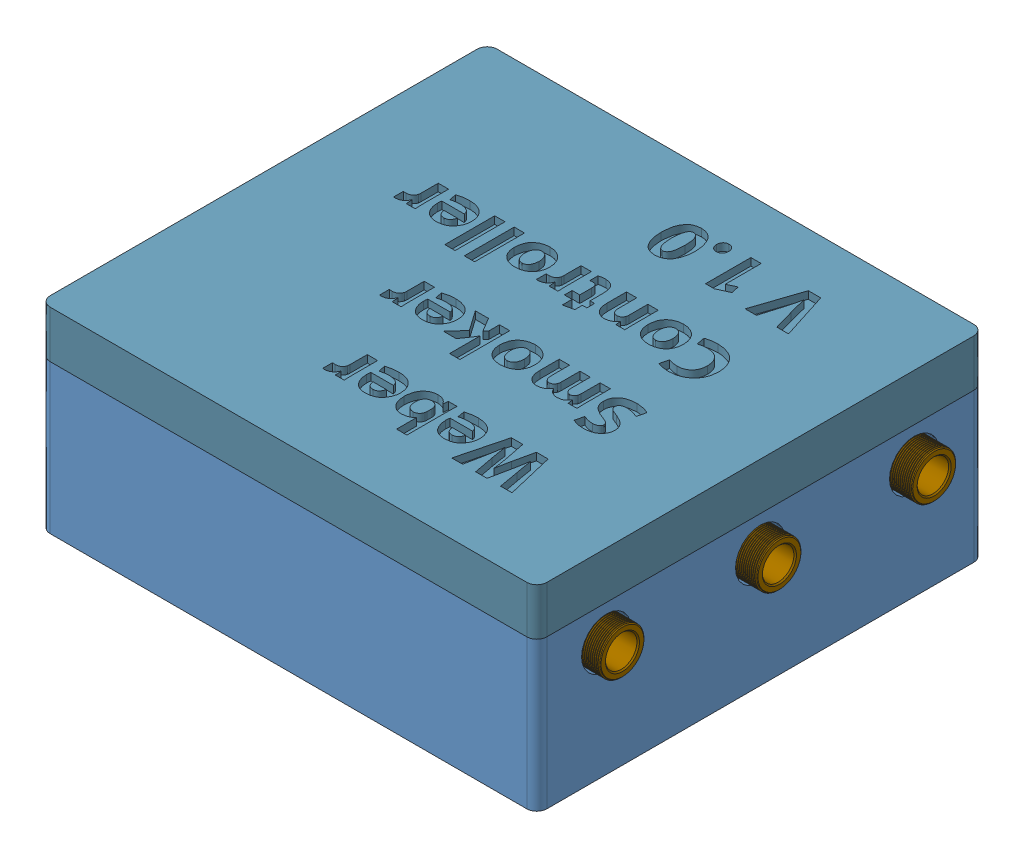
SolidWorks assembly controller, configuration Default. Lengths in mm.
Overall size (108.36 39.5 90).
121 component instances, 50 part files, 20 mates.
Components (placement in the parent):
- box-1: box [Default] at (28.3215 40.8238 49.104) size (100 35 90)
- adafruit esp8266 feather-1: adafruit esp8266 feather [Default] at (-8.3947 55.8238 40.0665) x (0 0 1) z (0 1 0) size (51.25 22.86 3.97)
  - adafruit esp8266 feather-1: adafruit esp8266 feather [Default] at origin size (50.8 22.86 1.6)
  - 0805NO_10UF-1: 0805NO_10UF [Default] at (21.3793 16.0687 1.6213) x (0.148132 -0.963382 0.223501) z (0.165546 0.24696 0.95478) size (2.2 1.45 1)
  - 0805NO_10_F-1: 0805NO_10_F [Default] at (11.049 12.192 1.6) x (-1 0 0) z (0 0 1) size (2.2 1.45 1)
  - 0805NO_10_F-2: 0805NO_10_F [Default] at (8.088 12.959 1.6) x (0 1 0) z (0 0 1) size (2.2 1.45 1)
  - 0805NO_10_F-3: 0805NO_10_F [Default] at (14.366 12.64 1.6) x (0 -1 0) z (0 0 1) size (2.2 1.45 1)
  - 0603NO_1UF-1: 0603NO_1UF [Default] at (12.302 4.775 1.6) x (0 -1 0) z (0 0 1) size (3 1.48 1)
  - CHIPLED_0805_NOOUTLINE_ORANGE-1: CHIPLED_0805_NOOUTLINE_ORANGE [Default] at (2.413 5.588 1.6) x (0 -1 0) z (0 0 1) size (1.25 2 1)
  - CHIPLED_0805_NOOUTLINE_RED-1: CHIPLED_0805_NOOUTLINE_RED [Default] at (2.8575 17.3355 1.6) x (0 -1 0) z (0 0 1) size (1.25 2 1)
  - SOD123_MBR120-1: SOD123_MBR120 [Default] at (17.907 18.796 1.6) x (-1 0 0) z (0 0 1) size (3.45 1.5 1)
  - QFN24_4MM_SMSC_CP2104-1: QFN24_4MM_SMSC_CP2104 [Default] at (16.256 6.477 1.6) size (5.38 4.1 1)
  - 1X16_ROUND_JP1_1X16_ROUND-1: 1X16_ROUND_JP1_1X16_ROUND [Default] at (25.4 1.27 1.6) x (-1 0 0) z (0 0 1) size (39.73 1.47 1)
  - 1X12_ROUND_JP3_1X12_ROUND-1: 1X12_ROUND_JP3_1X12_ROUND [Default] at (30.48 21.59 1.6) size (29.57 1.47 1)
  - SOT233_MMBT2222-1: SOT233_MMBT2222 [Default] at (24.003 8.001 1.6) x (-1 0 0) z (0 0 1) size (2.92 1.47 1)
  - SOT233_MMBT2222-2: SOT233_MMBT2222 [Default] at (24.003 14.986 1.6) size (2.92 1.47 1)
  - 0603NO_10K-1: 0603NO_10K [Default] at (24.257 18.923 1.6) x (-1 0 0) z (0 0 1) size (3 1.48 1)
  - 0603NO_10K-2: 0603NO_10K [Default] at (24.257 17.526 1.6) x (-1 0 0) z (0 0 1) size (3 1.48 1)
  - 0603NO_10K-3: 0603NO_10K [Default] at (24.003 11.938 1.6) x (-1 0 0) z (0 0 1) size (3 1.48 1)
  - 0603NO_10K-4: 0603NO_10K [Default] at (17.78 17.272 1.6) size (3 1.48 1)
  - 0603NO_10K-5: 0603NO_10K [Default] at (24.384 5.334 1.6) x (-1 0 0) z (0 0 1) size (3 1.48 1)
  - 0603NO_1K-1: 0603NO_1K [Default] at (6.223 4.191 1.6) size (3 1.48 1)
  - 0603NO_1K-2: 0603NO_1K [Default] at (5.588 21.082 1.6) x (0 -1 0) z (0 0 1) size (3 1.48 1)
  - _0603MP_10K-1: _0603MP_10K [Default] at (24.003 10.541 1.6) size (1.6 0.8 1)
  - 0603NO_4_7K-1: 0603NO_4_7K [Default] at (24.384 3.937 1.6) size (3 1.48 1)
  - 0603NO_10K_-1: 0603NO_10K_ [Default] at (20.828 12.7 1.6) x (0 -1 0) z (0 0 1) size (3 1.48 1)
  - _0603MP_1K-1: _0603MP_1K [Default] at (19.812 8.382 1.6) x (0 -1 0) z (0 0 1) size (1.6 0.8 1)
  - SOLDERJUMPER_CLOSEDWIRE_SJ1_SOLDERJUMPER_CLOSEDWIRE-1: SOLDERJUMPER_CLOSEDWIRE_SJ1_SOLDERJUMPER_CLOSEDWIRE [Default] at (12.827 9.779 1.6) x (-1 0 0) z (0 0 1) size (3.3 2.13 1)
  - BTN_KMR2_4_6X2_8_KMR2-1: BTN_KMR2_4_6X2_8_KMR2 [Default] at (9.398 6.35 1.6) x (0 -1 0) z (0 0 1) size (4.2 3.05 1)
  - ADAFRUIT_5MM_U_7_ADAFRUIT_5MM-1: ADAFRUIT_5MM_U_7_ADAFRUIT_5MM [Default] at (45.6565 13.9065 0) x (0 1 0) z (0 0 -1) size (4.88 4.87 1)
  - FEATHERLOGO_U_9_FEATHERLOGO-1: FEATHERLOGO_U_9_FEATHERLOGO [Default] at (30.6705 4.8895 0) x (-1 0 0) z (0 0 -1) size (24.3 11.26 1)
  - PCBFEATREV040_U_13_PCBFEATREV040-1: PCBFEATREV040_U_13_PCBFEATREV040 [Default] at (4.6355 11.2395 0) x (-1 0 0) z (0 0 -1) size (2.1 2.1 1)
  - ADAFRUIT_3_5MM_U_15_ADAFRUIT_3_5MM-1: ADAFRUIT_3_5MM_U_15_ADAFRUIT_3_5MM [Default] at (19.05 4.064 1.6) size (3.79 3.79 1)
  - HUZZAHLOGO_U_23_HUZZAHLOGO-1: HUZZAHLOGO_U_23_HUZZAHLOGO [Default] at (49.911 10.287 0) x (-1 0 0) z (0 0 -1) size (17.77 2.78 1)
  - FIDUCIAL_1MM_FIDUCIAL__-1: FIDUCIAL_1MM_FIDUCIAL__ [Default] at (10.795 20.066 1.6) x (0 -1 0) z (0 0 1) size (1.25 1.25 1)
  - FIDUCIAL_1MM_FIDUCIAL__-2: FIDUCIAL_1MM_FIDUCIAL__ [Default] at (41.5762 11.691 1.6) x (0 -1 0) z (0 0 1) size (1.25 1.25 1)
  - SOT235_SPX3819-1: SOT235_SPX3819 [Default] at (17.78 14.986 1.6) x (0 1 0) z (0 0 1) size (3.3 3 1)
  - SOT235_MCP73831T2ACI_OT-1: SOT235_MCP73831T2ACI_OT [Default] at (17.78 11.557 1.6) x (0 -1 0) z (0 0 1) size (3.3 3 1)
  - JSTPH2_JSTPH-1: JSTPH2_JSTPH [Default] at (10.795 19.304 1.6) size (8.2 7.6 1)
  - ESP12E_ESP12-1: ESP12E_ESP12 [Default] at (36.322 11.43 1.6) x (0 -1 0) z (0 0 1) size (16.13 24.06 1)
  - 4UCONN_20329_V2_20329-1: 4UCONN_20329_V2_20329 [Default] at (4.445 11.43 1.6) x (0 -1 0) z (0 0 1) size (10.1 6.4 1)
- adafruit max31850-1: adafruit max31850 [Default] at (16.5415 55.8238 55.4665) x (0 0 1) z (0 1 0) size (20.32 20.32 3.6)
  - adafruit max31850-1: adafruit max31850 [Default] at origin size (20.32 20.32 1.6)
  - 0805NO_10UF-1: 0805NO_10UF [Default] at (2.968 6 1.6) x (-1 0 0) z (0 0 1) size (2.2 1.45 1)
  - 0805NO_10UF-2: 0805NO_10UF [Default] at (2.874 12.638 1.6) size (2.2 1.45 1)
  - 0805NO_0_1UF-1: 0805NO_0_1UF [Default] at (10.46 10.476 1.6) size (2.2 1.45 1)
  - 0805_FERRITE-1: 0805_FERRITE [Default] at (8.4 12.257 1.6) size (3.8 2 1)
  - 0805_FERRITE-2: 0805_FERRITE [Default] at (12.082 12.257 1.6) x (-1 0 0) z (0 0 1) size (3.8 2 1)
  - FIDUCIAL_1MM_FIDUCIAL__-1: FIDUCIAL_1MM_FIDUCIAL__ [Default] at (13.43 9.952 1.6) size (1.25 1.25 1)
  - FIDUCIAL_1MM_FIDUCIAL__-2: FIDUCIAL_1MM_FIDUCIAL__ [Default] at (1.283 14.636 1.6) size (1.25 1.25 1)
  - SOLDERJUMPER_2WAY_OPEN_NOPASTE_SJ1_SOLDERJUMPER_2WAY_OPEN_NOPASTE-1: SOLDERJUMPER_2WAY_OPEN_NOPASTE_SJ1_SOLDERJUMPER_2WAY_OPEN_NOPASTE [Default] at (17.78 12.954 0) x (-1 0 0) z (0 0 -1) size (4.57 2.13 1)
  - SOLDERJUMPER_2WAY_OPEN_NOPASTE_SJ2_SOLDERJUMPER_2WAY_OPEN_NOPASTE-1: SOLDERJUMPER_2WAY_OPEN_NOPASTE_SJ2_SOLDERJUMPER_2WAY_OPEN_NOPASTE [Default] at (17.78 10.414 0) x (-1 0 0) z (0 0 -1) size (4.57 2.13 1)
  - SOLDERJUMPER_2WAY_OPEN_NOPASTE_SJ3_SOLDERJUMPER_2WAY_OPEN_NOPASTE-1: SOLDERJUMPER_2WAY_OPEN_NOPASTE_SJ3_SOLDERJUMPER_2WAY_OPEN_NOPASTE [Default] at (17.78 7.874 0) x (-1 0 0) z (0 0 -1) size (4.57 2.13 1)
  - SOLDERJUMPER_2WAY_OPEN_NOPASTE_SJ4_SOLDERJUMPER_2WAY_OPEN_NOPASTE-1: SOLDERJUMPER_2WAY_OPEN_NOPASTE_SJ4_SOLDERJUMPER_2WAY_OPEN_NOPASTE [Default] at (17.78 5.334 0) x (-1 0 0) z (0 0 -1) size (4.57 2.13 1)
  - ADAFRUIT_3_5MM_U_18_ADAFRUIT_3_5MM-1: ADAFRUIT_3_5MM_U_18_ADAFRUIT_3_5MM [Default] at (8.001 7.493 0) x (-1 0 0) z (0 0 -1) size (3.79 3.79 1)
  - ADAFRUIT_3_5MM_U_19_ADAFRUIT_3_5MM-1: ADAFRUIT_3_5MM_U_19_ADAFRUIT_3_5MM [Default] at (4.064 8.128 1.6) size (3.79 3.79 1)
  - TDFN10_3X4MM_MAX31850-1: TDFN10_3X4MM_MAX31850 [Default] at (10.206 7.73 1.6) x (0 -1 0) z (0 0 1) size (3.45 5.3 1)
  - SOT235_MIC52253_3-1: SOT235_MIC52253_3 [Default] at (2.366 9.034 1.6) size (3.3 3 1)
  - TERMBLOCK_1X23_5MM_3_5MM-1: TERMBLOCK_1X23_5MM_3_5MM [Default] at (10.16 16.637 1.6) x (-1 0 0) z (0 0 1) size (7.1 7.1 1)
- adafruit max31850-3: adafruit max31850 [Default] at (16.5415 56.3415 78.4665) x (0 0 1) z (0 1 0) size (20.32 20.32 3.6)
  - adafruit max31850-1: adafruit max31850 [Default] at origin size (20.32 20.32 1.6)
  - 0805NO_10UF-1: 0805NO_10UF [Default] at (2.968 6 1.6) x (-1 0 0) z (0 0 1) size (2.2 1.45 1)
  - 0805NO_10UF-2: 0805NO_10UF [Default] at (2.874 12.638 1.6) size (2.2 1.45 1)
  - 0805NO_0_1UF-1: 0805NO_0_1UF [Default] at (10.46 10.476 1.6) size (2.2 1.45 1)
  - 0805_FERRITE-1: 0805_FERRITE [Default] at (8.4 12.257 1.6) size (3.8 2 1)
  - 0805_FERRITE-2: 0805_FERRITE [Default] at (12.082 12.257 1.6) x (-1 0 0) z (0 0 1) size (3.8 2 1)
  - FIDUCIAL_1MM_FIDUCIAL__-1: FIDUCIAL_1MM_FIDUCIAL__ [Default] at (13.43 9.952 1.6) size (1.25 1.25 1)
  - FIDUCIAL_1MM_FIDUCIAL__-2: FIDUCIAL_1MM_FIDUCIAL__ [Default] at (1.283 14.636 1.6) size (1.25 1.25 1)
  - SOLDERJUMPER_2WAY_OPEN_NOPASTE_SJ1_SOLDERJUMPER_2WAY_OPEN_NOPASTE-1: SOLDERJUMPER_2WAY_OPEN_NOPASTE_SJ1_SOLDERJUMPER_2WAY_OPEN_NOPASTE [Default] at (17.78 12.954 0) x (-1 0 0) z (0 0 -1) size (4.57 2.13 1)
  - SOLDERJUMPER_2WAY_OPEN_NOPASTE_SJ2_SOLDERJUMPER_2WAY_OPEN_NOPASTE-1: SOLDERJUMPER_2WAY_OPEN_NOPASTE_SJ2_SOLDERJUMPER_2WAY_OPEN_NOPASTE [Default] at (17.78 10.414 0) x (-1 0 0) z (0 0 -1) size (4.57 2.13 1)
  - SOLDERJUMPER_2WAY_OPEN_NOPASTE_SJ3_SOLDERJUMPER_2WAY_OPEN_NOPASTE-1: SOLDERJUMPER_2WAY_OPEN_NOPASTE_SJ3_SOLDERJUMPER_2WAY_OPEN_NOPASTE [Default] at (17.78 7.874 0) x (-1 0 0) z (0 0 -1) size (4.57 2.13 1)
  - SOLDERJUMPER_2WAY_OPEN_NOPASTE_SJ4_SOLDERJUMPER_2WAY_OPEN_NOPASTE-1: SOLDERJUMPER_2WAY_OPEN_NOPASTE_SJ4_SOLDERJUMPER_2WAY_OPEN_NOPASTE [Default] at (17.78 5.334 0) x (-1 0 0) z (0 0 -1) size (4.57 2.13 1)
  - ADAFRUIT_3_5MM_U_18_ADAFRUIT_3_5MM-1: ADAFRUIT_3_5MM_U_18_ADAFRUIT_3_5MM [Default] at (8.001 7.493 0) x (-1 0 0) z (0 0 -1) size (3.79 3.79 1)
  - ADAFRUIT_3_5MM_U_19_ADAFRUIT_3_5MM-1: ADAFRUIT_3_5MM_U_19_ADAFRUIT_3_5MM [Default] at (4.064 8.128 1.6) size (3.79 3.79 1)
  - TDFN10_3X4MM_MAX31850-1: TDFN10_3X4MM_MAX31850 [Default] at (10.206 7.73 1.6) x (0 -1 0) z (0 0 1) size (3.45 5.3 1)
  - SOT235_MIC52253_3-1: SOT235_MIC52253_3 [Default] at (2.366 9.034 1.6) size (3.3 3 1)
  - TERMBLOCK_1X23_5MM_3_5MM-1: TERMBLOCK_1X23_5MM_3_5MM [Default] at (10.16 16.637 1.6) x (-1 0 0) z (0 0 1) size (7.1 7.1 1)
- battery-1: battery [Default] at (38.2207 45.8238 106.0886) size (47 8 62)
- FenderJack-1: FenderJack [Default] at (-19.0369 73.4119 116.1141) x (0 -0.003907 -0.999992) z (0 -0.999992 0.003907) size (21.76 31.52 19.89)
  - FenderJack_Cylinder-1: FenderJack_Cylinder [Default] at (5.059 3.4811 15.0685) size (15.24 10.86 15.24)
  - FenderJack_UpperTab-1: FenderJack_UpperTab [Default] at (5.059 13.4506 15.0685) x (0.866025 0 0.5) z (-0.5 0 0.866025) size (17.8 8.61 12.69)
  - FenderJack_UpperSiPlate-1: FenderJack_UpperSiPlate [Default] at (5.059 12.4346 15.0685) size (19.05 1.02 18.14)
  - FenderJack_LowerTab-1: FenderJack_LowerTab [Default] at (5.059 12.1806 15.0685) x (-1 0 0) z (0 0 -1) size (17.49 22.56 16.82)
  - FenderJack_LowerSiPlate-1: FenderJack_LowerSiPlate [Default] at (5.059 11.1646 15.0685) size (17.78 1.02 17.78)
- adafruit max31850-4: adafruit max31850 [Default] at (16.5415 55.8238 100.4665) x (0 0 1) z (0 1 0) size (20.32 20.32 3.6)
  - adafruit max31850-1: adafruit max31850 [Default] at origin size (20.32 20.32 1.6)
  - 0805NO_10UF-1: 0805NO_10UF [Default] at (2.968 6 1.6) x (-1 0 0) z (0 0 1) size (2.2 1.45 1)
  - 0805NO_10UF-2: 0805NO_10UF [Default] at (2.874 12.638 1.6) size (2.2 1.45 1)
  - 0805NO_0_1UF-1: 0805NO_0_1UF [Default] at (10.46 10.476 1.6) size (2.2 1.45 1)
  - 0805_FERRITE-1: 0805_FERRITE [Default] at (8.4 12.257 1.6) size (3.8 2 1)
  - 0805_FERRITE-2: 0805_FERRITE [Default] at (12.082 12.257 1.6) x (-1 0 0) z (0 0 1) size (3.8 2 1)
  - FIDUCIAL_1MM_FIDUCIAL__-1: FIDUCIAL_1MM_FIDUCIAL__ [Default] at (13.43 9.952 1.6) size (1.25 1.25 1)
  - FIDUCIAL_1MM_FIDUCIAL__-2: FIDUCIAL_1MM_FIDUCIAL__ [Default] at (1.283 14.636 1.6) size (1.25 1.25 1)
  - SOLDERJUMPER_2WAY_OPEN_NOPASTE_SJ1_SOLDERJUMPER_2WAY_OPEN_NOPASTE-1: SOLDERJUMPER_2WAY_OPEN_NOPASTE_SJ1_SOLDERJUMPER_2WAY_OPEN_NOPASTE [Default] at (17.78 12.954 0) x (-1 0 0) z (0 0 -1) size (4.57 2.13 1)
  - SOLDERJUMPER_2WAY_OPEN_NOPASTE_SJ2_SOLDERJUMPER_2WAY_OPEN_NOPASTE-1: SOLDERJUMPER_2WAY_OPEN_NOPASTE_SJ2_SOLDERJUMPER_2WAY_OPEN_NOPASTE [Default] at (17.78 10.414 0) x (-1 0 0) z (0 0 -1) size (4.57 2.13 1)
  - SOLDERJUMPER_2WAY_OPEN_NOPASTE_SJ3_SOLDERJUMPER_2WAY_OPEN_NOPASTE-1: SOLDERJUMPER_2WAY_OPEN_NOPASTE_SJ3_SOLDERJUMPER_2WAY_OPEN_NOPASTE [Default] at (17.78 7.874 0) x (-1 0 0) z (0 0 -1) size (4.57 2.13 1)
  - SOLDERJUMPER_2WAY_OPEN_NOPASTE_SJ4_SOLDERJUMPER_2WAY_OPEN_NOPASTE-1: SOLDERJUMPER_2WAY_OPEN_NOPASTE_SJ4_SOLDERJUMPER_2WAY_OPEN_NOPASTE [Default] at (17.78 5.334 0) x (-1 0 0) z (0 0 -1) size (4.57 2.13 1)
  - ADAFRUIT_3_5MM_U_18_ADAFRUIT_3_5MM-1: ADAFRUIT_3_5MM_U_18_ADAFRUIT_3_5MM [Default] at (8.001 7.493 0) x (-1 0 0) z (0 0 -1) size (3.79 3.79 1)
  - ADAFRUIT_3_5MM_U_19_ADAFRUIT_3_5MM-1: ADAFRUIT_3_5MM_U_19_ADAFRUIT_3_5MM [Default] at (4.064 8.128 1.6) size (3.79 3.79 1)
  - TDFN10_3X4MM_MAX31850-1: TDFN10_3X4MM_MAX31850 [Default] at (10.206 7.73 1.6) x (0 -1 0) z (0 0 1) size (3.45 5.3 1)
  - SOT235_MIC52253_3-1: SOT235_MIC52253_3 [Default] at (2.366 9.034 1.6) size (3.3 3 1)
  - TERMBLOCK_1X23_5MM_3_5MM-1: TERMBLOCK_1X23_5MM_3_5MM [Default] at (10.16 16.637 1.6) x (-1 0 0) z (0 0 1) size (7.1 7.1 1)
- FenderJack-2: FenderJack [Default] at (95.7645 78.2319 44.3702) x (0 0.111847 0.993725) z (0 -0.993725 0.111847) size (21.76 31.52 19.89)
  - FenderJack_Cylinder-1: FenderJack_Cylinder [Default] at (5.059 3.4811 15.0685) size (15.24 10.86 15.24)
  - FenderJack_UpperTab-1: FenderJack_UpperTab [Default] at (5.059 13.4506 15.0685) x (0.866025 0 0.5) z (-0.5 0 0.866025) size (17.8 8.61 12.69)
  - FenderJack_UpperSiPlate-1: FenderJack_UpperSiPlate [Default] at (5.059 12.4346 15.0685) size (19.05 1.02 18.14)
  - FenderJack_LowerTab-1: FenderJack_LowerTab [Default] at (5.059 12.1806 15.0685) x (-1 0 0) z (0 0 -1) size (17.49 22.56 16.82)
  - FenderJack_LowerSiPlate-1: FenderJack_LowerSiPlate [Default] at (5.059 11.1646 15.0685) size (17.78 1.02 17.78)
- FenderJack-3: FenderJack [Default] at (95.0038 77.8014 105.5145) x (0 0.171504 0.985183) z (0 -0.985183 0.171504) size (21.76 31.52 19.89)
  - FenderJack_Cylinder-1: FenderJack_Cylinder [Default] at (5.059 3.4811 15.0685) size (15.24 10.86 15.24)
  - FenderJack_UpperTab-1: FenderJack_UpperTab [Default] at (5.059 13.4506 15.0685) x (0.866025 0 0.5) z (-0.5 0 0.866025) size (17.8 8.61 12.69)
  - FenderJack_UpperSiPlate-1: FenderJack_UpperSiPlate [Default] at (5.059 12.4346 15.0685) size (19.05 1.02 18.14)
  - FenderJack_LowerTab-1: FenderJack_LowerTab [Default] at (5.059 12.1806 15.0685) x (-1 0 0) z (0 0 -1) size (17.49 22.56 16.82)
  - FenderJack_LowerSiPlate-1: FenderJack_LowerSiPlate [Default] at (5.059 11.1646 15.0685) size (17.78 1.02 17.78)
- FenderJack-4: FenderJack [Default] at (95.6098 78.524 76.0366) x (0 0.06625 0.997803) z (0 -0.997803 0.06625) size (21.76 31.52 19.89)
  - FenderJack_Cylinder-1: FenderJack_Cylinder [Default] at (5.059 3.4811 15.0685) size (15.24 10.86 15.24)
  - FenderJack_UpperTab-1: FenderJack_UpperTab [Default] at (5.059 13.4506 15.0685) x (0.866025 0 0.5) z (-0.5 0 0.866025) size (17.8 8.61 12.69)
  - FenderJack_UpperSiPlate-1: FenderJack_UpperSiPlate [Default] at (5.059 12.4346 15.0685) size (19.05 1.02 18.14)
  - FenderJack_LowerTab-1: FenderJack_LowerTab [Default] at (5.059 12.1806 15.0685) x (-1 0 0) z (0 0 -1) size (17.49 22.56 16.82)
  - FenderJack_LowerSiPlate-1: FenderJack_LowerSiPlate [Default] at (5.059 11.1646 15.0685) size (17.78 1.02 17.78)
- lid-1: lid [Default] at (88.2853 80.3238 127.0828) x (-1 0 0) z (0 0 1) size (100 9.5 90)
Mates (geometry in assembly coordinates):
- Concentric1: concentric aligned: circle of box-1; circle of adafruit esp8266 feather-1/adafruit esp8266 feather-1
- Coincident1: coincident anti-aligned: circle of box-1; plane of adafruit esp8266 feather-1/adafruit esp8266 feather-1 through (-8.3947 55.8238 40.0665) normal (0 -1 0)
- Concentric9: concentric anti-aligned: cylinder of box-1 through (34.3215 50.8238 81.0065) axis (0 1 0) radius 1.1; cylinder of adafruit max31850-3/adafruit max31850-1 through (34.3215 57.9415 81.0065) axis (0 -1 0) radius 1.25
- Concentric10: concentric aligned: cylinder of box-1 through (34.3215 50.8238 96.2465) axis (0 1 0) radius 1.1; circle of adafruit max31850-3/adafruit max31850-1
- Concentric11: concentric anti-aligned: cylinder of box-1 through (34.3215 50.8238 58.0065) axis (0 1 0) radius 1.1; cylinder of adafruit max31850-1/adafruit max31850-1 through (34.3215 57.4238 58.0065) axis (0 -1 0) radius 1.25
- Concentric12: concentric anti-aligned: cylinder of box-1 through (34.3215 50.8238 73.2465) axis (0 1 0) radius 1.1; cylinder of adafruit max31850-1/adafruit max31850-1 through (34.3215 57.4238 73.2465) axis (0 -1 0) radius 1.25
- Coincident3: coincident: plane of box-1 through (34.3215 55.8238 73.2465) normal (0 1 0); line of adafruit max31850-1/adafruit max31850-1 through (36.8615 55.8238 73.2465) axis (0 0 -1)
- Coincident4: coincident: plane of box-1 through (28.3215 45.8238 49.104) normal (0 1 0); line of battery-1 through (38.2207 45.8238 106.0886) axis (1 0 0)
- Concentric13: concentric anti-aligned: circle of box-1; circle of FenderJack-1/FenderJack_Cylinder-1
- Concentric14: concentric anti-aligned: cylinder of box-1 through (34.3215 50.8238 118.2465) axis (0 1 0) radius 1.1; cylinder of adafruit max31850-4/adafruit max31850-1 through (34.3215 57.4238 118.2465) axis (0 -1 0) radius 1.25
- Concentric15: concentric aligned: cylinder of box-1 through (34.3215 50.8238 103.0065) axis (0 1 0) radius 1.1; circle of adafruit max31850-4/adafruit max31850-1
- Coincident5: coincident anti-aligned: plane of box-1 through (34.3215 55.8238 103.0065) normal (0 1 0); plane of adafruit max31850-4/adafruit max31850-1 through (16.5415 55.8238 100.4665) normal (0 -1 0)
- Concentric16: concentric anti-aligned: circle of box-1; circle of FenderJack-2/FenderJack_Cylinder-1
- Concentric17: concentric anti-aligned: circle of box-1; circle of FenderJack-4/FenderJack_Cylinder-1
- Concentric18: concentric anti-aligned: circle of box-1; circle of FenderJack-3/FenderJack_Cylinder-1
- Coincident6: coincident anti-aligned: plane of box-1 through (28.3215 45.8238 49.104) normal (0 1 0); plane of battery-1 through (38.2207 45.8238 106.0886) normal (0 -1 0)
- Coincident7: coincident anti-aligned: plane of box-1 through (85.2207 45.8238 124.6702) normal (-1 0 0); plane of battery-1 through (85.2207 53.8238 106.0886) normal (1 0 0)
- Coincident8: coincident anti-aligned: plane of box-1 through (28.3215 70.8238 49.104) normal (0 1 0); plane of lid-1 through (88.2853 70.8238 127.0828) normal (0 -1 0)
- Coincident9: coincident anti-aligned: line of box-1 through (-9.7147 70.8238 127.0828) axis (1 0 0); line of lid-1 through (86.2853 70.8238 127.0828) axis (-1 0 0)
- Coincident10: coincident anti-aligned: line of box-1 through (88.2853 70.8238 125.0828) axis (0 0 -1); line of lid-1 through (88.2853 70.8238 39.0828) axis (0 0 1)
